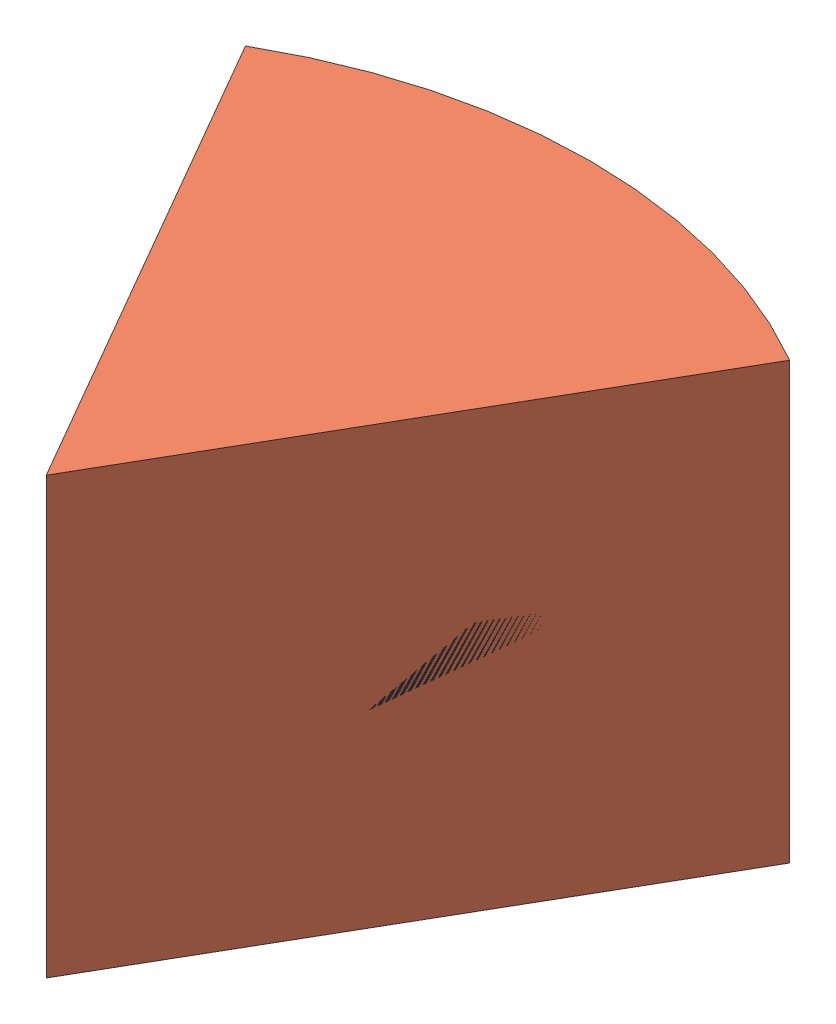
SolidWorks assembly Sample, configuration Défaut. Lengths in mm.
Overall size (25 20 25).
2 component instances, 2 part files, 2 mates.
Components (placement in the parent):
- Bone-2: Bone [Défaut] at origin size (45 3 45)
- PMMA-1: PMMA [Défaut] at origin size (50 20 50)
Mates (geometry in assembly coordinates):
- Coïncidente2: coincident: point of assembly; point of Bone-2; point of assembly
- Coïncidente3: coordinate: unknown of PMMA-1
